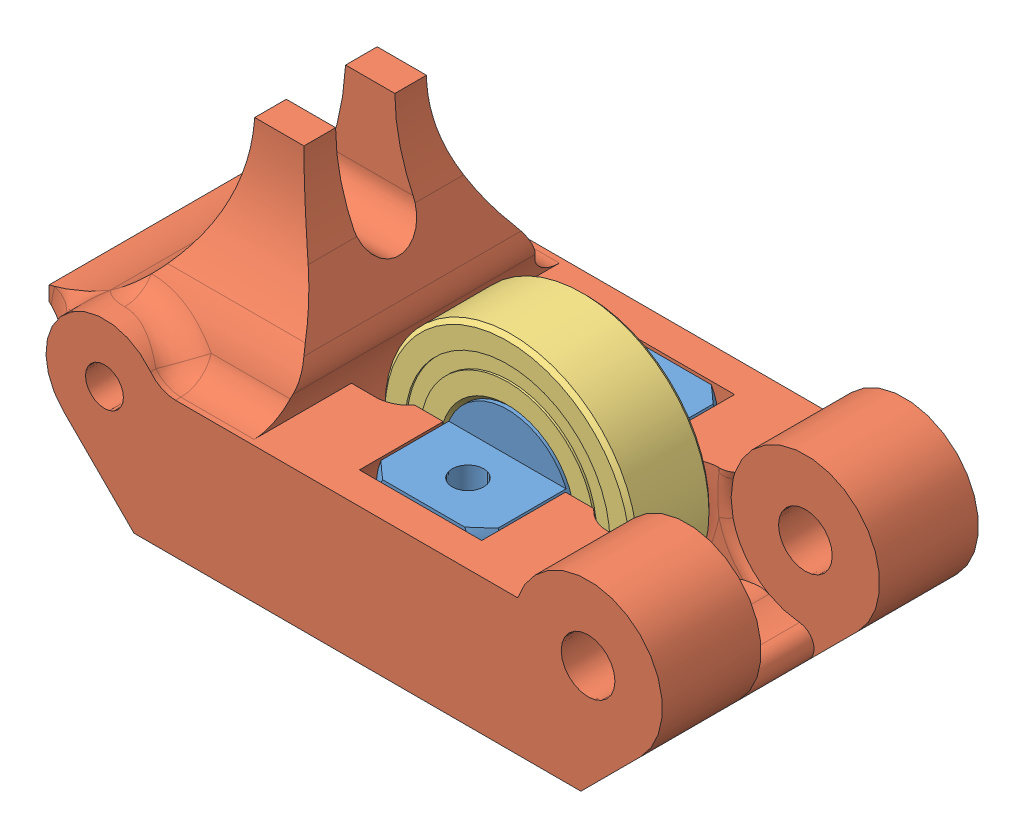
SolidWorks assembly Assem1, configuration Default. Lengths in mm.
Overall size (41.13 21.37 20.11).
3 component instances, 3 part files, 5 mates.
Components (placement in the parent):
- IdlerPin-15mm-1: IdlerPin-15mm [Default] at (-5.8462 7.0103 24.7229) x (0 1 0) z (0 0 1) size (7.5 8 15.6)
- IdlerBlock-1: IdlerBlock [Default] at (-5.8462 7.0103 24.7229) x (0 1 0) z (0 0 1) size (20.98 41.13 20.11)
- Bearing-688-1: Bearing-688 [7804K117] at (-5.8462 7.0103 24.7229) size (16 16 5)
Mates (geometry in assembly coordinates):
- Concentric1: concentric anti-aligned: cylinder of Bearing-688-1 through (-5.8462 7.0103 16.9229) axis (0 0 1) radius 4; line of Bearing-688-1 through (-5.8462 7.0103 22.2229) axis (0 0 -1)
- Coincident2: coincident aligned: plane of Bearing-688-1 through (-5.8462 7.0103 24.7229) normal (0 0 1); plane of Bearing-688-1 through (-5.8462 7.0103 24.7229) normal (0 0 1)
- Coincident3: coincident aligned: plane of Bearing-688-1 through (-5.8462 7.0103 24.7229) normal (0 0 1); plane of ? through (-5.8462 7.0103 24.7229) normal (0 0 1)
- Parallel3: parallel aligned: plane of ? through (-5.8462 8.5103 16.9229) normal (0 1 0); plane of ? through (-5.8462 8.5103 14.7229) normal (0 1 0)
- Concentric3: concentric anti-aligned: cylinder of Bearing-688-1 through (-5.8462 7.0103 16.9229) axis (0 0 1) radius 4; cylinder of ? through (-5.8462 7.0103 32.7229) axis (0 0 -1) radius 4.15
